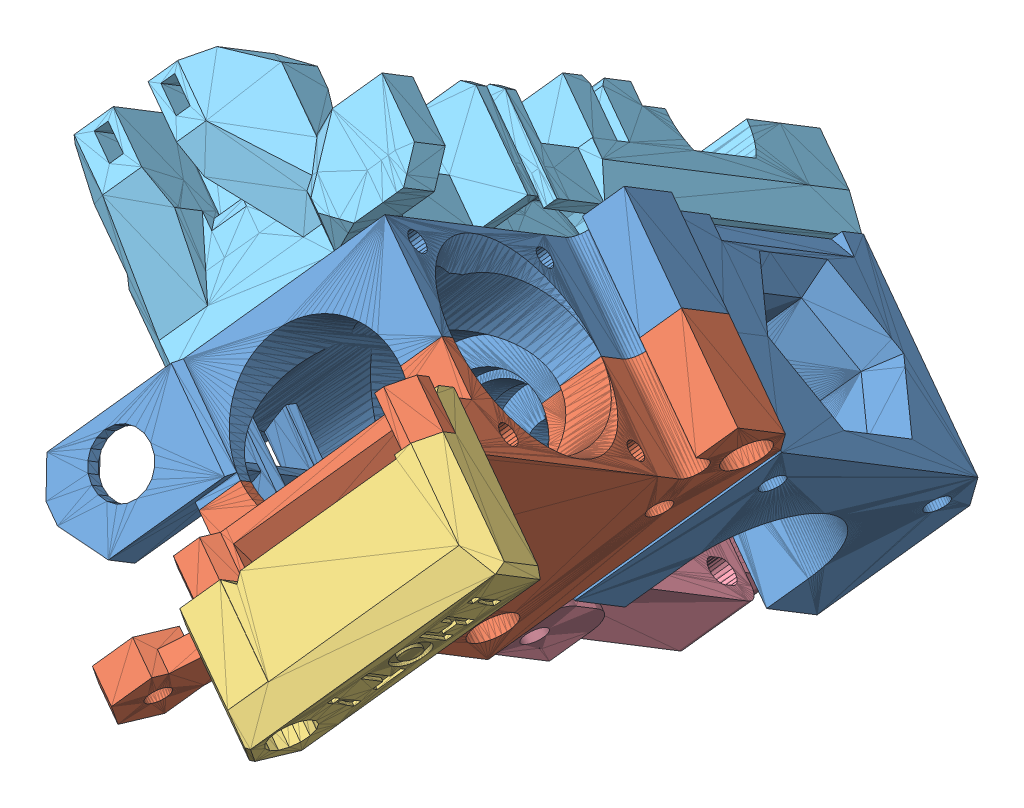
SolidWorks assembly Сборка-Экструдер, configuration По умолчанию. Lengths in mm.
Overall size (91.13 117.41 130.56).
5 component instances, 5 part files, 12 mates.
Components (placement in the parent):
- extruder-body-1: extruder-body [По умолчанию] at (-114.6403 111.7317 -44.3415) x (0.55902 0.682781 -0.470432) z (0.827282 -0.497399 0.261149) size (60.5 87 30)
- extruder-cover-1: extruder-cover [По умолчанию] at (-81.03 122.1444 -16.8701) x (-0.55902 -0.682781 0.470432) z (-0.827282 0.497399 -0.261149) size (64.05 60.8 14.8)
- fan-nozzle-1: fan-nozzle [По умолчанию] at (-62.4073 131.1225 6.3331) x (0.55902 0.682781 -0.470432) z (-0.827282 0.497399 -0.261149) size (38.8 10.05 23)
- extruder-idler-2: extruder-idler [По умолчанию] at (-102.7784 88.4502 -64.0364) x (0.827282 -0.497399 0.261149) z (0.55902 0.682781 -0.470432) size (25.5 57 10)
- x-carriage-1: x-carriage [По умолчанию] at (-93.9073 151.5364 -34.206) x (0.55902 0.682781 -0.470432) z (-0.827282 0.497399 -0.261149) size (52 93 25)
Mates (geometry in assembly coordinates):
- Совпадение6: coincident aligned: plane of ? through (-108.2149 145.3448 -0.6746) normal (0.055685 0.535168 0.842909); plane of ? through (-73.7003 153.122 -7.8925) normal (0.055685 0.535168 0.842909)
- Совпадение7: coincident anti-aligned: plane of ? through (-83.0428 152.5379 -9.2773) normal (0.827282 -0.497399 0.261149); plane of ? through (-82.9359 153.6029 -7.5877) normal (-0.827282 0.497399 -0.261149)
- Совпадение8: coincident aligned: plane of ? through (-79.5941 157.6844 -10.3999) normal (0.55902 0.682781 -0.470432); plane of ? through (-77.0153 154.7462 -11.6) normal (0.55902 0.682781 -0.470432)
- Совпадение12: coincident anti-aligned: plane of ? through (-66.6821 156.745 3.58) normal (-0.055685 -0.535168 -0.842909); plane of ? through (-70.4802 159.538 2.0576) normal (0.055685 0.535168 0.842909)
- Совпадение13: coincident anti-aligned: plane of ? through (-97.9806 139.5923 -44.052) normal (0.827282 -0.497399 0.261149); plane of ? through (-93.6739 149.0904 -39.6044) normal (-0.827282 0.497399 -0.261149)
- Совпадение15: coincident anti-aligned: plane of ? through (-67.4082 154.4567 1.5217) normal (0.827282 -0.497399 0.261149); plane of ? through (-66.4026 157.0863 3.3448) normal (-0.827282 0.497399 -0.261149)
- Совпадение16: coincident aligned: plane of ? through (-64.877 160.0242 4.1074) normal (0.55902 0.682781 -0.470432); plane of ? through (-64.8738 160.0551 4.1561) normal (0.55902 0.682781 -0.470432)
- Совпадение17: coincident aligned: plane of ? through (-101.0511 106.9078 -78.7717) normal (-0.055685 -0.535168 -0.842909); plane of ? through (-104.5979 125.8519 -90.5651) normal (-0.055685 -0.535168 -0.842909)
- Совпадение18: coincident aligned: plane of ? through (-107.9726 105.4654 -77.3987) normal (-0.55902 -0.682781 0.470432); plane of ? through (-107.9726 105.4654 -77.3987) normal (-0.55902 -0.682781 0.470432)
- Совпадение19: coincident anti-aligned: plane of ? through (-108.3436 108.8861 -40.989) normal (0.827282 -0.497399 0.261149); plane of extruder-idler-2 through (-109.0426 102.1678 -51.5706) normal (-0.827282 0.497399 -0.261149)
- Совпадение20: coincident aligned: plane of ? through (-114.5482 112.6166 -42.9477) normal (-0.55902 -0.682781 0.470432); plane of extruder-idler-2 through (-109.0426 102.1678 -51.5706) normal (-0.55902 -0.682781 0.470432)
- Расстояние1: distance = 0.1 mm anti-aligned: plane of extruder-cover-1 through (-102.2199 104.3777 -40.2557) normal (-0.055685 -0.535168 -0.842909); plane of extruder-idler-2 through (-105.076 112.1514 -45.1212) normal (0.055685 0.535168 0.842909)
